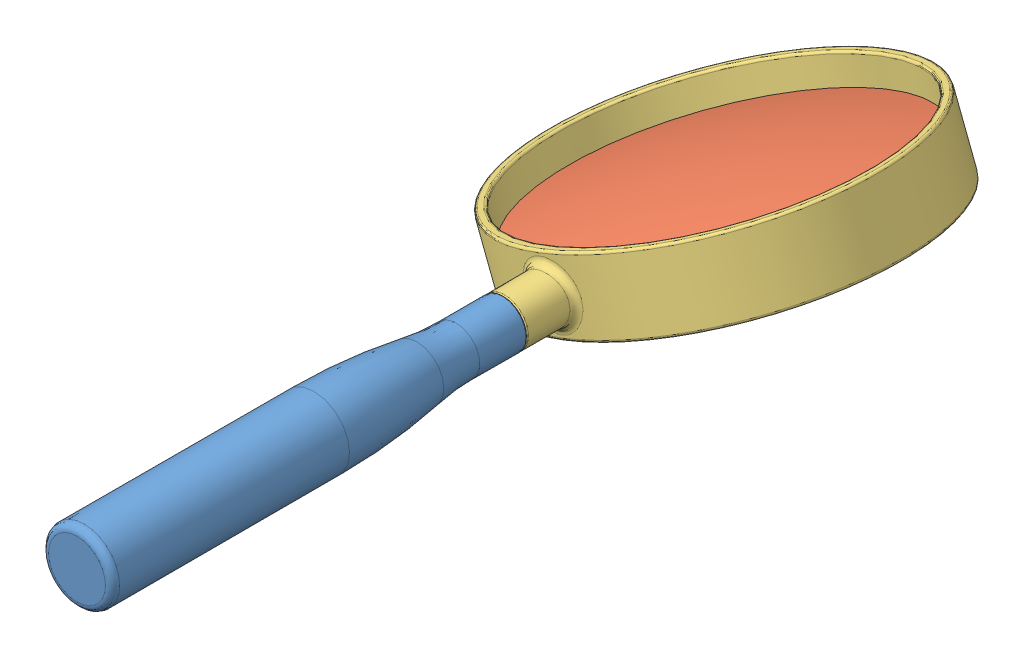
SolidWorks assembly MagnifyingGlassAssembly, configuration Default. Lengths in mm.
Overall size (74.44 40.62 174).
3 component instances, 3 part files, 4 mates.
Components (placement in the parent):
- Handle-1: Handle [Default] at (38.0724 41.8474 43.3889) size (15 15 100)
- Lens-1: Lens [Default] at (38.0724 41.8474 -3.6111) x (0.933026 0.359809 0) z (0 0 1) size (70 10 70)
- Ring-1: Ring [Default] at (38.0724 41.8474 -3.6111) x (0.933026 0.359809 0) z (0 0 1) size (74 15 84)
Mates (geometry in assembly coordinates):
- Coincident1: coincident: plane of Handle-1 through (38.0724 44.8474 43.3889) normal (0 0 -1); plane of Ring-1 through (38.0724 41.8474 43.3889) normal (0 0 1)
- Concentric2: concentric: cylinder of Handle-1 through (38.0724 41.8474 -78.0283) axis (0 0 -1) radius 3; cylinder of Ring-1 through (38.0724 41.8474 33.3889) axis (0 0 1) radius 3
- Distance1: distance = 0 mm: cylinder of Lens-1 through (24.0862 78.1152 -3.6111) axis (-0.359809 0.933026 0) radius 35; cylinder of Ring-1 through (32.582 56.0845 -3.6111) axis (-0.359809 0.933026 0) radius 35
- Coincident2: coincident: axis of Handle-1 through (38.0724 41.8474 43.3889) axis (0 0 -1); line of Lens-1 through (38.0724 41.8474 -84.5111) axis (0 0 1)
